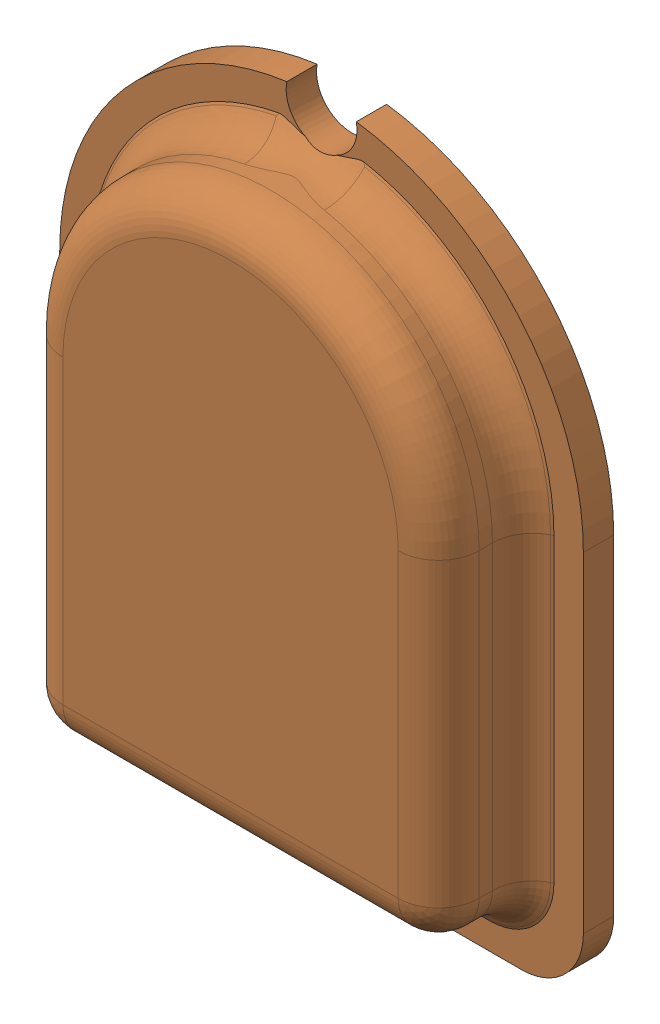
SolidWorks assembly new中间过程, configuration 默认. Lengths in mm.
Overall size (25.9 32.24 6).
2 component instances, 2 part files, 0 mates.
Components (placement in the parent):
- Skin0.2-1: Skin0.2 [默认] at (-119.2503 39.3851 -2.6) size (24.3 30.49 5.2)
- Skin1-1: Skin1 [默认] at (-119.2503 39.3851 -2.6) size (25.9 32.24 6)
